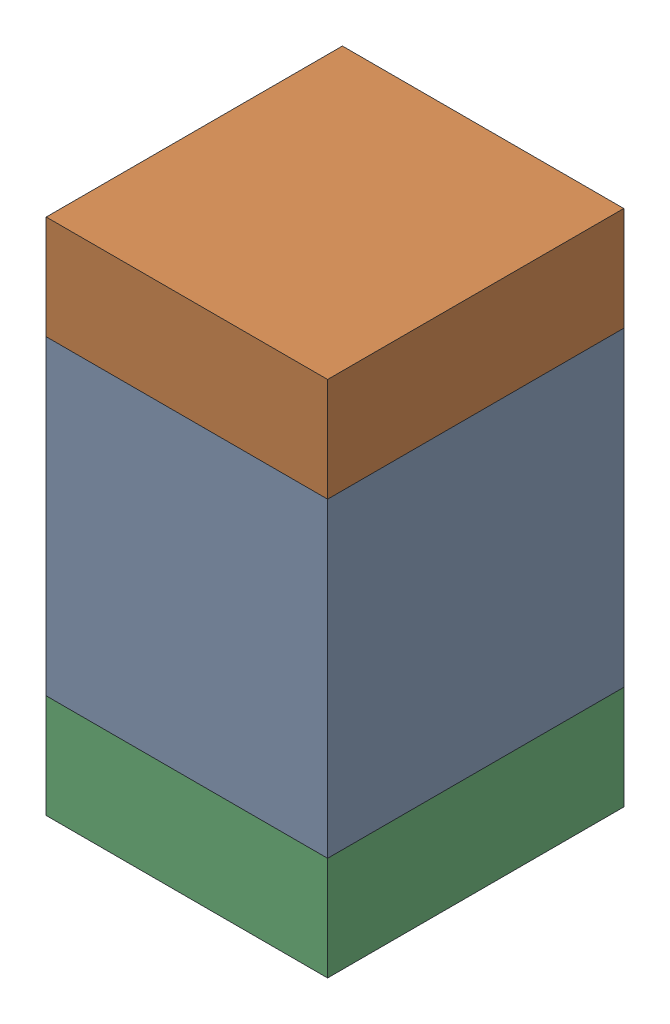
SolidWorks assembly C308_2PCB, configuration Default. Lengths in mm.
Overall size (0.95 1.75 1).
6 component instances, 2 part files, 0 mates.
Components (placement in the parent):
- 761616384-1: 761616384 [Default] at (124 93.4 0) size (0.95 1.05 1)
  - Extruded_5-1: Extruded_5 [Default] at origin size (0.95 1.05 1)
- 761616520-1: 761616520 [Default] at (124 94.1 0) size (0.95 0.35 1)
  - Extruded_6-1: Extruded_6 [Default] at origin size (0.95 0.35 1)
- 761616520-2: 761616520 [Default] at (124 92.7 0) size (0.95 0.35 1)
  - Extruded_6-1: Extruded_6 [Default] at origin size (0.95 0.35 1)
